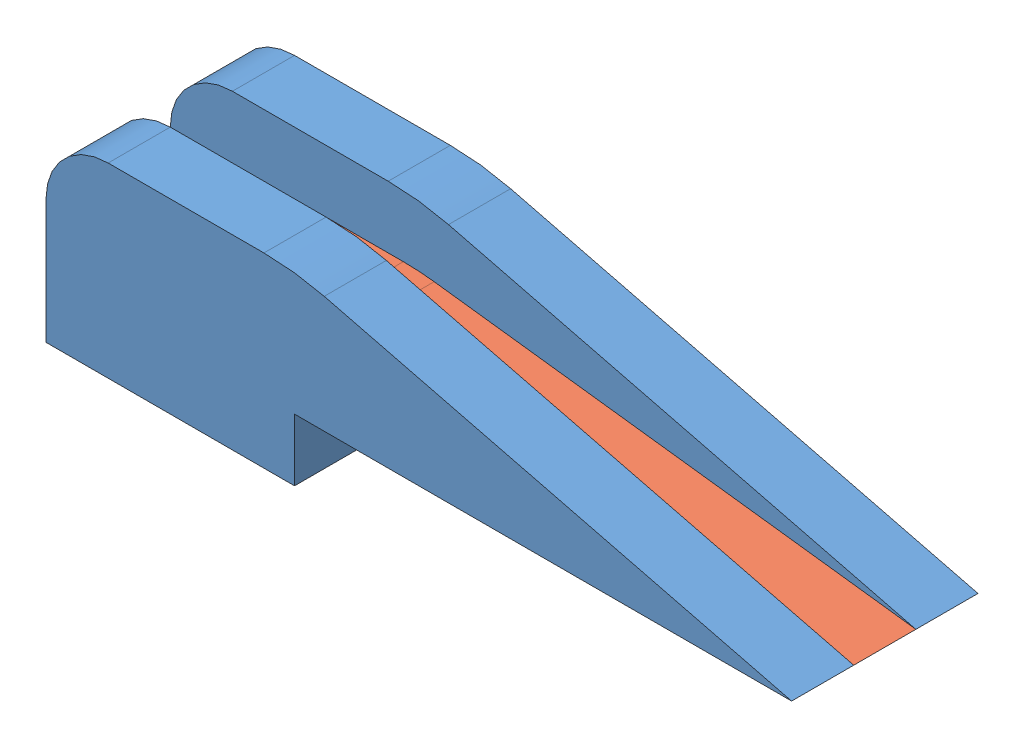
SolidWorks assembly Wedge Assembly, configuration Default. Lengths in mm.
Overall size (38.1 9.53 9.53).
3 component instances, 2 part files, 3 mates.
Components (placement in the parent):
- transfer wedge guide rails-1: transfer wedge guide rails [Default] at (552.5028 158.4468 -73.9775) x (-1 0 0) z (0 0 -1) size (38.1 9.52 3.17)
- transfer wedge-1: transfer wedge [Default] at (552.5028 158.4468 -70.8025) x (-1 0 0) z (0 0 -1) size (38.1 6.35 3.17)
- transfer wedge guide rails-2: transfer wedge guide rails [Default] at (552.5028 158.4468 -67.6275) x (-1 0 0) z (0 0 -1) size (38.1 9.52 3.17)
Mates (geometry in assembly coordinates):
- Coincident529: coincident anti-aligned: plane of transfer wedge guide rails-1 through (525.5393 152.0968 -73.9775) normal (0 0 1); plane of transfer wedge-1 through (526.3121 148.9218 -73.9775) normal (0 0 -1)
- Coincident536: coincident aligned: plane of transfer wedge guide rails-1 through (514.4028 161.6218 -77.1525) normal (-1 0 0); plane of transfer wedge guide rails-2 through (514.4028 161.6218 -70.8025) normal (-1 0 0)
- Coincident534: coincident anti-aligned: plane of transfer wedge-1 through (526.3121 148.9218 -70.8025) normal (0 0 1); plane of transfer wedge guide rails-2 through (525.5393 152.0968 -70.8025) normal (0 0 -1)
